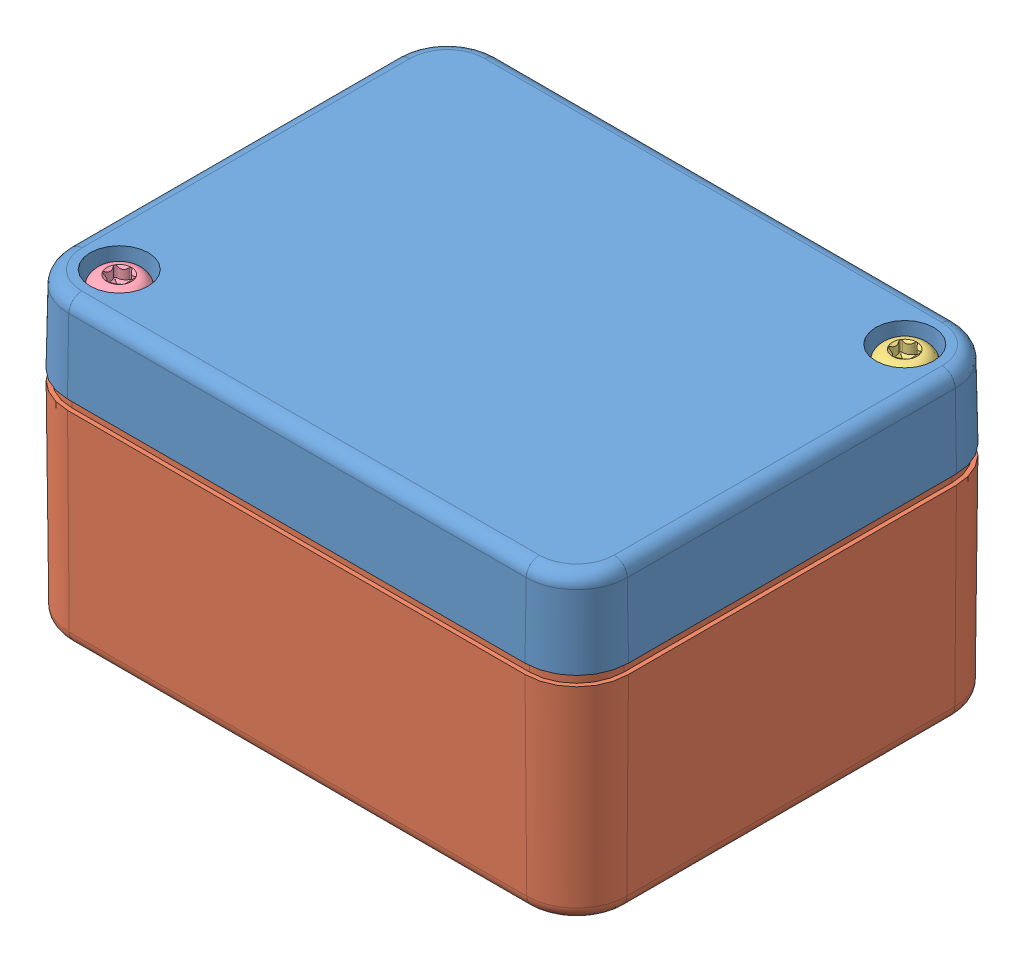
SolidWorks assembly rb32p04_10_, configuration Default. Lengths in mm.
Overall size (65 34.99 50).
9 component instances, 9 part files, 0 mates.
Components (placement in the parent):
- RB32-X04Y REV C(Default)-1: RB32-X04Y REV C(Default) [Default] at origin size (65 10 50)
- RB32X10Y REV C(Default)-1: RB32X10Y REV C(Default) [Default] x (-1 0 0) z (0 0 1) size (64.98 26.97 49.98)
- 6023_Pan_Head_screw_torx_head-4-40_Rev_B-1: 6023_Pan_Head_screw_torx_head-4-40_Rev_B [Default] at (26.4999 -17.94 -19) x (1 0 0) z (0 1 0) size (5.56 5.56 27.69)
- 6023_Pan_Head_screw_torx_head-4-40_Rev_B-1-1: 6023_Pan_Head_screw_torx_head-4-40_Rev_B-1 [Default] at (-26.4999 -17.94 19) x (1 0 0) z (0 1 0) size (5.56 5.56 27.69)
- 6102_4-40_threaded insert-1: 6102_4-40_threaded insert [Default] at (26.4999 -6.096 -19) x (-0.837169 0 -0.546944) z (-0.546944 0 0.837169) size (5.82 5.08 5.82)
- 6102_4-40_threaded insert-1-1: 6102_4-40_threaded insert-1 [Default] at (-26.4999 -6.096 19) x (-0.837169 0 -0.546944) z (-0.546944 0 0.837169) size (5.82 5.08 5.82)
- 6022 #10-16 HL Pan HD-1: 6022 #10-16 HL Pan HD [Default] at (-18.9992 -17.018 0) x (1 0 0) z (0 1 0) size (8.18 8.18 9.67)
- 6022 #10-16 HL Pan HD-1-1: 6022 #10-16 HL Pan HD-1 [Default] at (18.9992 -17.018 0) x (1 0 0) z (0 1 0) size (8.18 8.18 9.67)
- 8032 RB32 O ring Rev A-1: 8032 RB32 O ring Rev A [Default] at origin size (62.56 2.03 47.57)
